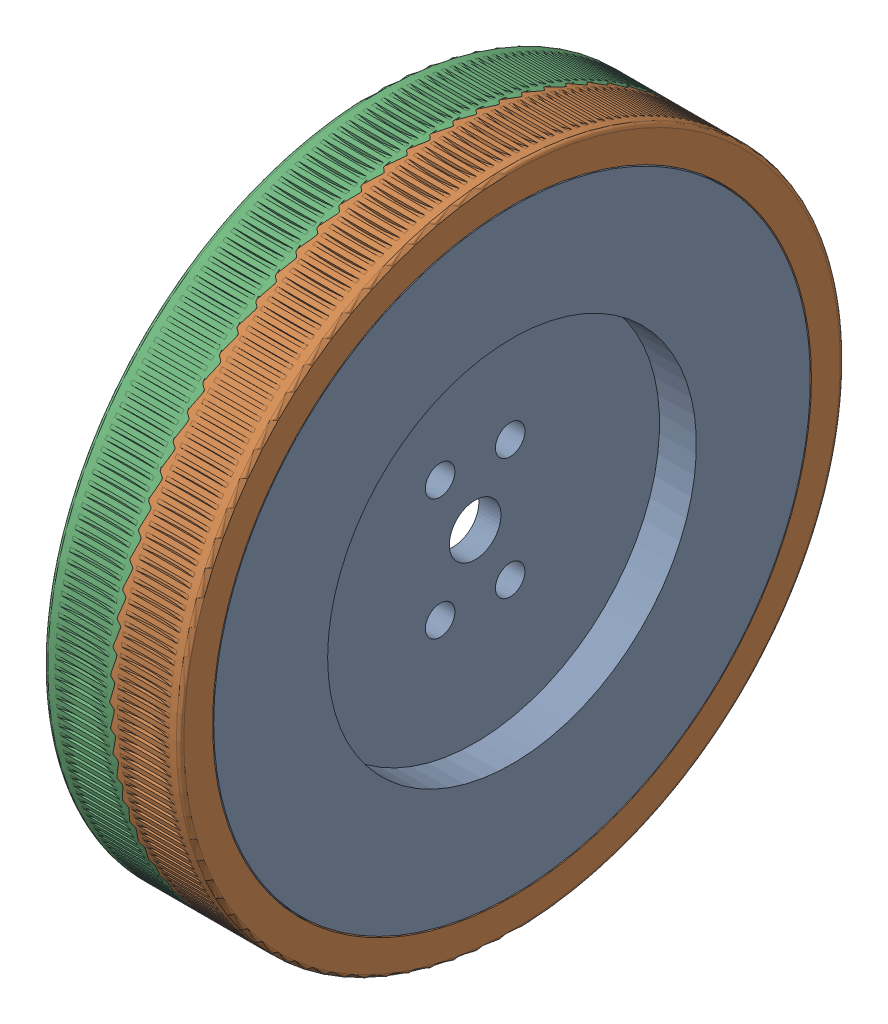
SolidWorks assembly Mirror3ajla, configuration Default. Lengths in mm.
Overall size (20 91.33 91.33).
3 component instances, 2 part files, 4 mates.
Components (placement in the parent):
- MirrorTombour-1: MirrorTombour [Défaut] at (26.609 38.7622 -75.4412) size (20 87 87)
- Mirrorcwatchou 3ajla pululu-1: Mirrorcwatchou 3ajla pululu [Default] at (24.609 38.7622 -75.4412) x (0 0 1) z (-1 0 0) size (90 90 10)
- Mirrorcwatchou 3ajla pululu-2: Mirrorcwatchou 3ajla pululu [Default] at (16.159 38.7622 -75.4412) x (0 0.014895 -0.999889) z (-1 0 0) size (90 90 10)
Mates (geometry in assembly coordinates):
- Concentric1: concentric anti-aligned: circle of MirrorTombour-1; circle of Mirrorcwatchou 3ajla pululu-1
- Concentric2: concentric anti-aligned: circle of MirrorTombour-1; circle of Mirrorcwatchou 3ajla pululu-2
- Coincident1: coincident aligned: plane of MirrorTombour-1 through (16.159 38.7622 -75.4412) normal (-1 0 0); plane of Mirrorcwatchou 3ajla pululu-2 through (16.159 38.7622 -75.4412) normal (-1 0 0)
- Coincident2: coincident aligned: plane of MirrorTombour-1 through (34.609 78.7622 -75.4412) normal (1 0 0); plane of Mirrorcwatchou 3ajla pululu-1 through (34.609 38.7622 -75.4412) normal (1 0 0)
